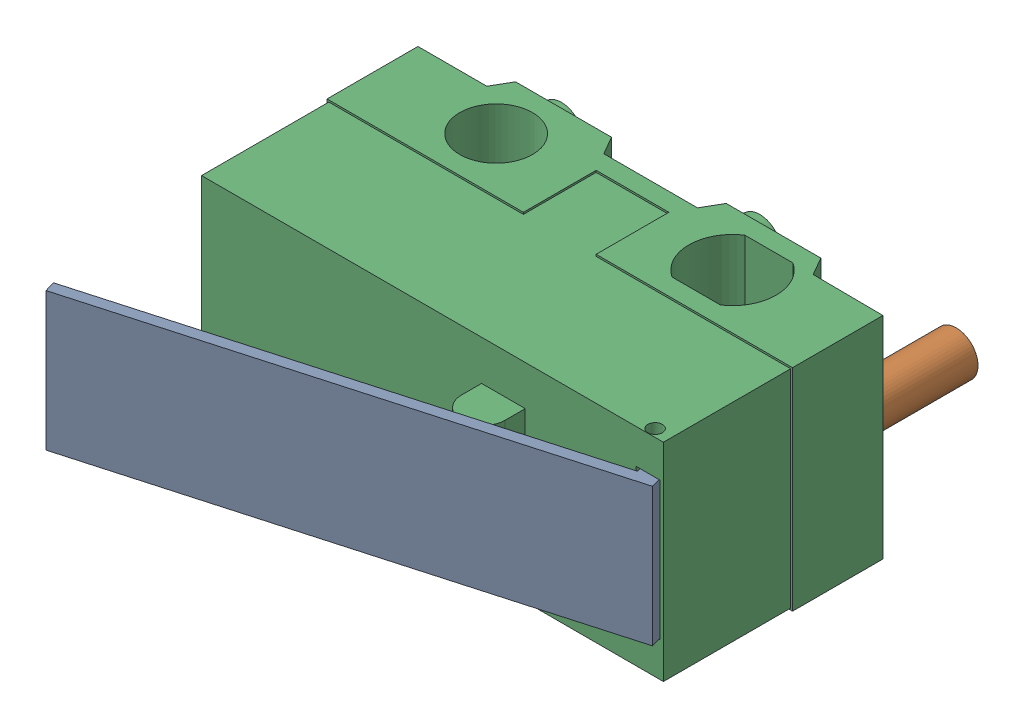
SolidWorks assembly KW10 Microswitch v2 v1, configuration Default. Lengths in mm.
Overall size (13.18 5.8 12.93).
5 component instances, 3 part files, 0 mates.
Components (placement in the parent):
- Component2-1: Component2 [Default] at (-0.4015 5 5) x (-1 0 0) z (0 0 1) size (13.18 5.8 12.93)
  - Component3-1: Component3 [Default] at origin size (13.08 3.8 4.39)
    - Component6-1: Component6 [Default] at origin size (13.08 3.8 4.39)
  - Component7-1: Component7 [Default] at origin size (1.2 1.2 3)
  - Component8-1: Component8 [Default] at origin size (12.8 5.8 10.15)
